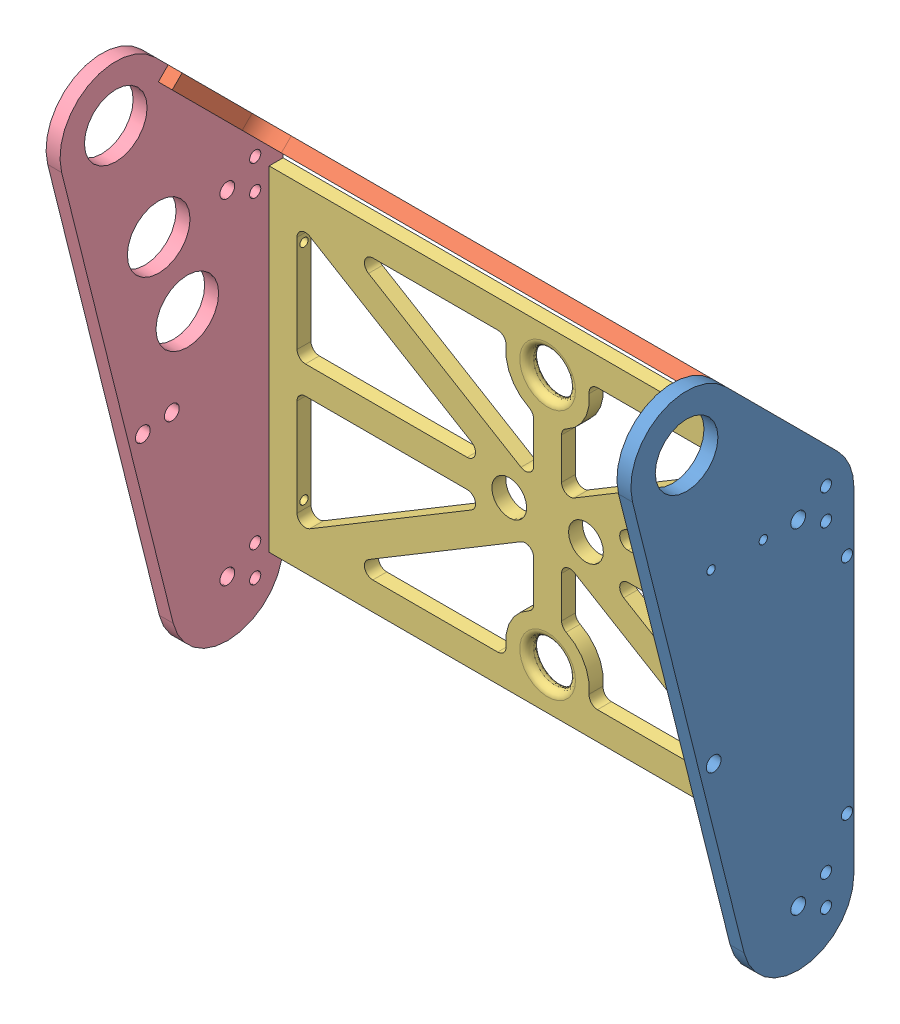
SolidWorks assembly 2018-305-A, configuration Default. Lengths in mm.
Overall size (266.32 254 101.6).
4 component instances, 4 part files, 16 mates.
Components (placement in the parent):
- 2018-305-D001-1: 2018-305-D001 [Default] at (177.8 0 0) size (6.35 254 101.6)
- 2018-305-D002-2: 2018-305-D002 [Default] at (50.9905 7.5717 -19.3691) x (0 -0.707107 -0.707107) z (1 0 0) size (63.5 6.35 253.62)
- 2018-305-D003-1: 2018-305-D003 [Default] at (50.9905 -50.8 -69.85) x (0 -1 0) z (1 0 0) size (152.4 6.35 253.62)
- 2018-305-D004-1: 2018-305-D004 [Default] at (-82.169 0 0) size (6.35 254 101.6)
Mates (geometry in assembly coordinates):
- Coincident1: coincident aligned: plane of 2018-305-D001-1 through (177.8 0 0) normal (0 1 0); plane of assembly through (0 0 0) normal (0 1 0)
- Coincident2: coincident aligned: plane of 2018-305-D001-1 through (177.8 0 0) normal (0 0 1); plane of assembly through (0 0 0) normal (0 0 1)
- Distance1: distance = 177.8 mm aligned: plane of assembly through (0 0 0) normal (1 0 0); plane of 2018-305-D001-1 through (177.8 0 0) normal (1 0 0)
- Parallel1: parallel aligned: plane of 2018-305-D004-1 through (-82.169 0 0) normal (0 1 0); plane of assembly through (0 0 0) normal (0 1 0)
- Coincident7: coincident aligned: plane of 2018-305-D001-1 through (184.15 -32.8395 -68.7605) normal (0 0.707107 -0.707107); plane of 2018-305-D002-2 through (177.8 12.0618 -23.8592) normal (0 0.707107 -0.707107)
- Coincident8: coincident aligned: line of 2018-305-D001-1 through (184.15 -32.8395 -68.7605) axis (-1 0 0); line of 2018-305-D002-2 through (177.8 -32.8395 -68.7605) axis (-1 0 0)
- Coincident9: coincident anti-aligned: plane of 2018-305-D001-1 through (177.8 0 0) normal (-1 0 0); plane of 2018-305-D002-2 through (177.8 7.5717 -19.3691) normal (1 0 0)
- Coincident10: coincident aligned: plane of 2018-305-D001-1 through (184.15 -203.2 -76.2) normal (0 0 -1); plane of 2018-305-D003-1 through (177.8 -50.8 -76.2) normal (0 0 -1)
- Coincident11: coincident anti-aligned: plane of 2018-305-D001-1 through (177.8 0 0) normal (-1 0 0); plane of 2018-305-D003-1 through (177.8 -50.8 -69.85) normal (1 0 0)
- Coincident12: coincident: line of 2018-305-D001-1 through (184.15 -203.2 -76.2) axis (-1 0 0); plane of 2018-305-D003-1 through (177.8 -203.2 -69.85) normal (0 -1 0)
- Concentric3: concentric aligned: cylinder of 2018-305-D001-1 through (184.15 0 0) axis (1 0 0) radius 14.2875; cylinder of 2018-305-D004-1 through (-75.819 0 0) axis (1 0 0) radius 14.2875
- Coincident13: coincident aligned: plane of 2018-305-D001-1 through (184.15 -203.2 -76.2) normal (0 0 -1); plane of 2018-305-D004-1 through (-75.819 -203.2 -76.2) normal (0 0 -1)
- Coincident14: coincident anti-aligned: plane of 2018-305-D002-2 through (-75.819 7.5717 -19.3691) normal (-1 0 0); plane of 2018-305-D004-1 through (-75.819 0 0) normal (1 0 0)
- Coincident15: coincident: plane of 2018-305-D003-1 through (177.8 -50.8 -76.2) normal (0 0 -1); plane of ? through (12.8905 -203.2 -76.2) normal (0 0 1)
- Coincident16: coincident: plane of 2018-305-D003-1 through (177.8 -203.2 -69.85) normal (0 -1 0); plane of ? through (12.8905 -203.2 -76.2) normal (0 -1 0)
- Coincident17: coincident anti-aligned: circle of 2018-305-D003-1; cylinder of ? through (50.9905 -184.15 -76.2) axis (0 0 1) radius 9.525
